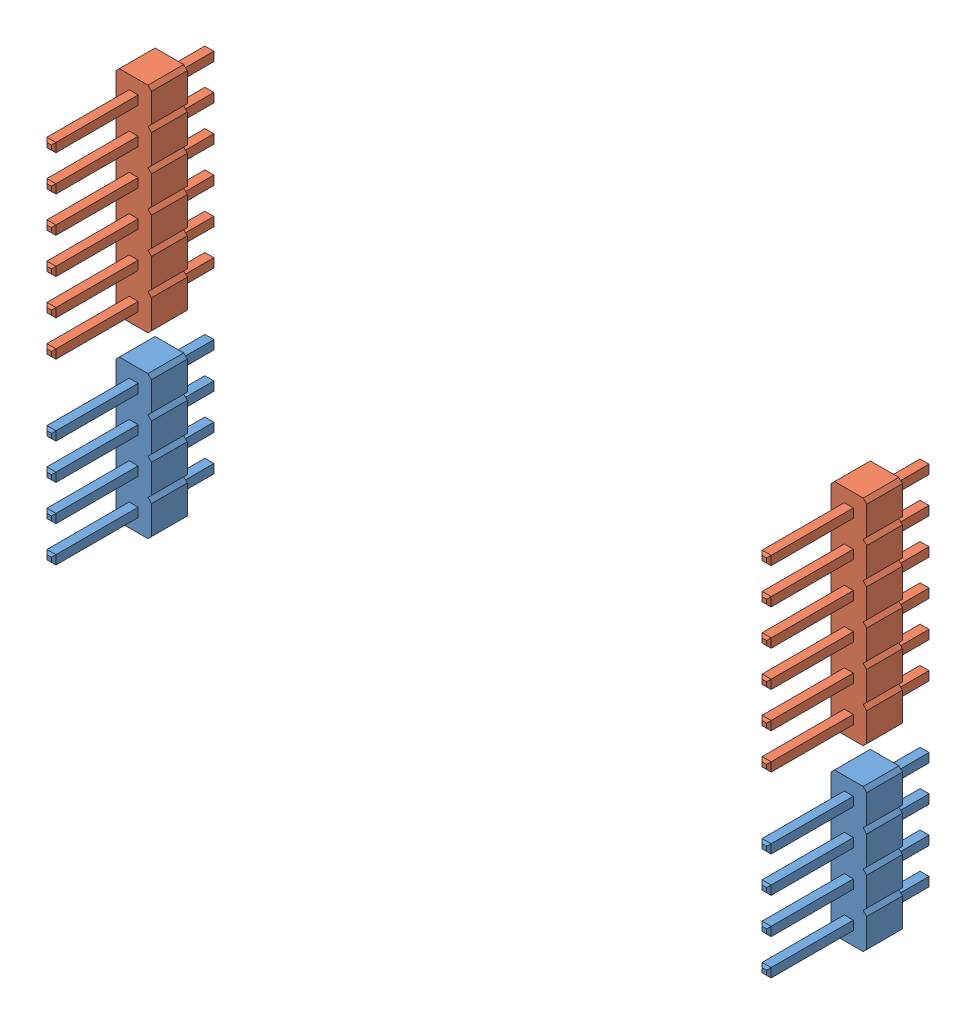
SolidWorks assembly 直排针, configuration 默认. Lengths in mm.
Overall size (53.34 27.9 11.54).
4 component instances, 2 part files, 3 mates.
Components (placement in the parent):
- PinHeader_1x04_P2.54mm_Vertical-1: PinHeader_1x04_P2.54mm_Vertical [默认] at (36.7073 -12.4802 -2.77) size (2.54 10.16 11.54)
- PinHeader_1x06_P2.54mm_Vertical.step-1: PinHeader_1x06_P2.54mm_Vertical.step [默认] at (36.7073 5.2598 -2.77) size (2.54 15.24 11.54)
- PinHeader_1x06_P2.54mm_Vertical.step-2: PinHeader_1x06_P2.54mm_Vertical.step [默认] at (-14.0927 5.2598 -2.77) size (2.54 15.24 11.54)
- PinHeader_1x04_P2.54mm_Vertical-2: PinHeader_1x04_P2.54mm_Vertical [默认] at (-14.0927 -12.4802 -2.77) size (2.54 10.16 11.54)
Mates (geometry in assembly coordinates):
- 重合1: coincident aligned: plane of PinHeader_1x04_P2.54mm_Vertical-1 through (37.9773 -21.1162 -2.77) normal (1 0 0); plane of PinHeader_1x06_P2.54mm_Vertical.step-1 through (37.9773 -8.4562 -2.77) normal (1 0 0)
- 重合3: coincident aligned: plane of PinHeader_1x04_P2.54mm_Vertical-1 through (36.7073 -16.2902 -0.23) normal (0 0 1); plane of PinHeader_1x06_P2.54mm_Vertical.step-1 through (36.7073 -1.0902 -0.23) normal (0 0 1)
- 距离1: distance = 2.5 mm anti-aligned: plane of PinHeader_1x06_P2.54mm_Vertical.step-1 through (35.6913 -8.7102 -2.77) normal (0 -1 0); plane of PinHeader_1x04_P2.54mm_Vertical-1 through (37.7233 -11.2102 -2.77) normal (0 1 0)
